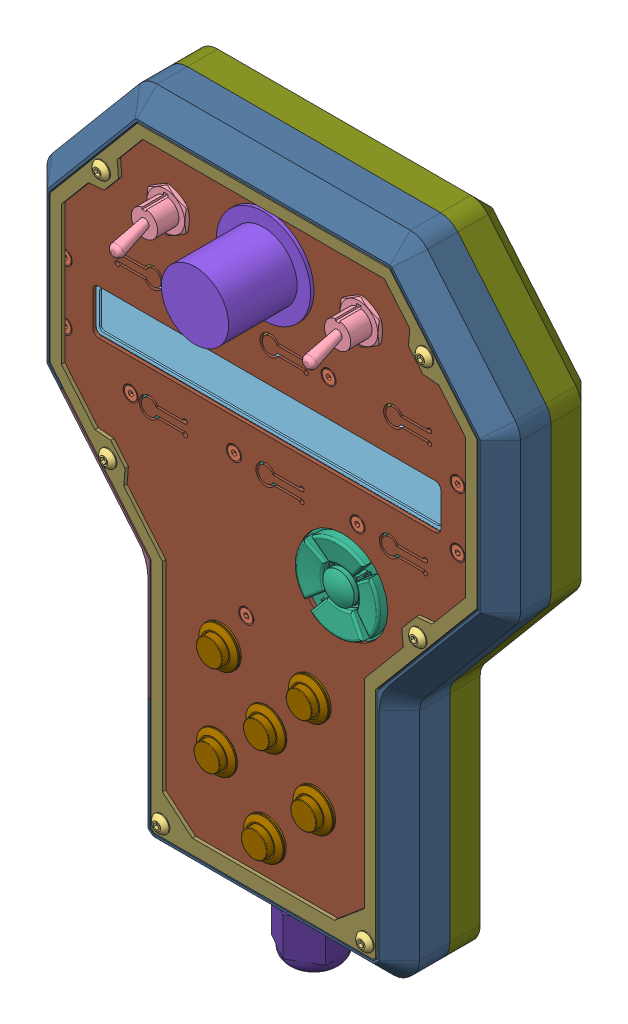
SolidWorks assembly Montagem, configuration Valor predeterminado. Lengths in mm.
Overall size (211 315 75.5).
59 component instances, 18 part files, 139 mates.
Components (placement in the parent):
- hex nut style 1 gradeab_din-3: hex nut style 1 gradeab_din [Hexagon Nut ISO 4032 - M4 - W - N] at (-95.2029 -0.5297 -15.05) x (-0.766044 -0.642788 0) z (0 0 1) size (7 8.08 3.2)
- hex nut style 1 gradeab_din-4: hex nut style 1 gradeab_din [Hexagon Nut ISO 4032 - M4 - W - N] at (42.9071 -0.5197 -15.05) x (0.766044 -0.642788 0) z (0 0 1) size (7 8.08 3.2)
- hex nut style 1 gradeab_din-5: hex nut style 1 gradeab_din [Hexagon Nut ISO 4032 - M4 - W - N] at (-69.6429 -49.9305 1.45) x (0.5 0.866025 0) z (0 0 1) size (7 8.08 3.2)
- hex nut style 1 gradeab_din-6: hex nut style 1 gradeab_din [Hexagon Nut ISO 4032 - M4 - W - N] at (33.6932 120.5695 1.45) x (0.766044 0.642788 0) z (0 0 1) size (7 8.08 3.2)
- hex nut style 1 gradeab_din-7: hex nut style 1 gradeab_din [Hexagon Nut ISO 4032 - M4 - W - N] at (17.3571 -99.7712 1.45) size (7 8.08 3.2)
- hex nut style 1 gradeab_din-8: hex nut style 1 gradeab_din [Hexagon Nut ISO 4032 - M4 - W - N] at (-85.979 120.5695 1.45) x (0.766044 -0.642788 0) z (0 0 1) size (7 8.08 3.2)
- hex nut style 1 gradeab_din-9: hex nut style 1 gradeab_din [Hexagon Nut ISO 4032 - M4 - W - N] at (-69.6429 -99.7712 1.45) size (7 8.08 3.2)
- hex nut style 1 gradeab_din-10: hex nut style 1 gradeab_din [Hexagon Nut ISO 4032 - M4 - W - N] at (45.8324 109.2141 -7.45) x (0.939693 -0.34202 0) z (0 0 -1) size (7 8.08 3.2)
- hex nut style 1 gradeab_din-11: hex nut style 1 gradeab_din [Hexagon Nut ISO 4032 - M4 - W - N] at (-71.6429 -129.7045 -7.45) x (0.5 0.866025 0) z (0 0 -1) size (7 8.08 3.2)
- hex nut style 1 gradeab_din-12: hex nut style 1 gradeab_din [Hexagon Nut ISO 4032 - M4 - W - N] at (19.3571 -129.7045 -7.45) x (1 0 0) z (0 0 -1) size (7 8.08 3.2)
- hex nut style 1 gradeab_din-13: hex nut style 1 gradeab_din [Hexagon Nut ISO 4032 - M4 - W - N] at (-98.1182 109.2141 -7.45) x (-0.939693 -0.34202 0) z (0 0 -1) size (7 8.08 3.2)
- socket countersunk head screw_din-8: socket countersunk head screw_din [DIN 7991 - M3 x 16 --- 12.8C] at (58.8311 39.2309 9.75) x (0 0 -1) z (1 0 0) size (16 5.7 5.7)
- socket countersunk head screw_din-9: socket countersunk head screw_din [DIN 7991 - M3 x 16 --- 12.8C] at (-86.7826 27.8805 9.75) x (0 0 -1) z (-0.923728 -0.383049 0) size (16 5.7 5.7)
- socket countersunk head screw_din-10: socket countersunk head screw_din [DIN 7991 - M3 x 16 --- 12.8C] at (-116.1689 65.7309 9.75) x (0 0 -1) z (-0.923728 -0.383049 0) size (16 5.7 5.7)
- socket countersunk head screw_din-11: socket countersunk head screw_din [DIN 7991 - M3 x 16 --- 12.8C] at (1.3536 78.245 9.75) x (0 0 -1) z (0.923728 0.383049 0) size (16 5.7 5.7)
- socket countersunk head screw_din-12: socket countersunk head screw_din [DIN 7991 - M3 x 16 --- 12.8C] at (-116.1689 39.2309 9.75) x (0 0 -1) z (-0.923728 -0.383049 0) size (16 5.7 5.7)
- socket countersunk head screw_din-13: socket countersunk head screw_din [DIN 7991 - M3 x 16 --- 12.8C] at (-50.6464 78.245 9.75) x (0 0 -1) z (0.923728 0.383049 0) size (16 5.7 5.7)
- socket countersunk head screw_din-14: socket countersunk head screw_din [DIN 7991 - M3 x 16 --- 12.8C] at (58.8311 65.7309 9.75) x (0 0 -1) z (0.923728 0.383049 0) size (16 5.7 5.7)
- socket countersunk head screw_din-15: socket countersunk head screw_din [DIN 7991 - M3 x 16 --- 12.8C] at (14.2174 27.8805 9.75) x (0 0 -1) z (1 0 0) size (16 5.7 5.7)
- socket countersunk head screw_din-16: socket countersunk head screw_din [DIN 7991 - M3 x 16 --- 12.8C] at (-40.7826 27.8805 9.75) x (0 0 -1) z (0.277326 0.960776 0) size (16 5.7 5.7)
- socket countersunk head screw_din-17: socket countersunk head screw_din [DIN 7991 - M3 x 16 --- 12.8C] at (-35.2826 -32.1195 9.75) x (0 0 -1) z (-0.305827 0.952087 0) size (16 5.7 5.7)
- hex nut style 1 gradeab_din-15: hex nut style 1 gradeab_din [Hexagon Nut ISO 4032 - M3 - W - N] at (-40.7826 27.8805 -1.3414) x (0.012479 -0.999922 0) z (0 0 -1) size (5.5 6.35 2.4)
- hex nut style 1 gradeab_din-16: hex nut style 1 gradeab_din [Hexagon Nut ISO 4032 - M3 - W - N] at (-50.6464 78.245 -1.3414) x (0.904381 -0.426726 0) z (0 0 -1) size (5.5 6.35 2.4)
- hex nut style 1 gradeab_din-17: hex nut style 1 gradeab_din [Hexagon Nut ISO 4032 - M3 - W - N] at (1.3536 78.245 -1.3414) x (-0.993944 0.109886 0) z (0 0 -1) size (5.5 6.35 2.4)
- hex nut style 1 gradeab_din-18: hex nut style 1 gradeab_din [Hexagon Nut ISO 4032 - M3 - W - N] at (14.2174 27.8805 -1.3414) x (-0.816279 -0.577658 0) z (0 0 -1) size (5.5 6.35 2.4)
- hex nut style 1 gradeab_din-19: hex nut style 1 gradeab_din [Hexagon Nut ISO 4032 - M3 - W - N] at (-86.7826 27.8805 -1.3414) x (-0.525463 -0.850817 0) z (0 0 -1) size (5.5 6.35 2.4)
- hex nut style 1 gradeab_din-20: hex nut style 1 gradeab_din [Hexagon Nut ISO 4032 - M3 - W - N] at (-116.1689 65.7309 -4.818) x (0.297598 -0.954691 0) z (0 0 -1) size (5.5 6.35 2.4)
- hex nut style 1 gradeab_din-21: hex nut style 1 gradeab_din [Hexagon Nut ISO 4032 - M3 - W - N] at (-116.1689 39.2309 -4.818) x (0.646896 0.762578 0) z (0 0 -1) size (5.5 6.35 2.4)
- hex nut style 1 gradeab_din-22: hex nut style 1 gradeab_din [Hexagon Nut ISO 4032 - M3 - W - N] at (58.8311 65.7309 -4.818) x (0.923728 0.383049 0) z (0 0 -1) size (5.5 6.35 2.4)
- hex nut style 1 gradeab_din-23: hex nut style 1 gradeab_din [Hexagon Nut ISO 4032 - M3 - W - N] at (58.8311 39.2309 -4.818) x (0.923728 0.383049 0) z (0 0 -1) size (5.5 6.35 2.4)
- hex nut style 1 gradeab_din-24: hex nut style 1 gradeab_din [Hexagon Nut ISO 4032 - M3 - W - N] at (-35.2826 -32.1195 -1.3414) x (0.05846 -0.99829 0) z (0 0 -1) size (5.5 6.35 2.4)
- socket button head screw_iso-9: socket button head screw_iso [ISO 7380 - M4 x 16 --- 16N] at (45.8295 109.2085 13.45) x (0 0 -1) z (1 0 0) size (18.2 7.6 7.6)
- socket button head screw_iso-10: socket button head screw_iso [ISO 7380 - M4 x 16 --- 16N] at (-98.1153 109.2085 13.45) x (0 0 -1) z (0.767389 -0.641182 0) size (18.2 7.6 7.6)
- socket button head screw_iso-11: socket button head screw_iso [ISO 7380 - M4 x 16 --- 16N] at (-71.6429 -129.7005 13.45) x (0 0 -1) z (1 0 0) size (18.2 7.6 7.6)
- socket button head screw_iso-12: socket button head screw_iso [ISO 7380 - M4 x 16 --- 16N] at (19.3571 -129.7005 13.45) x (0 0 -1) z (1 0 0) size (18.2 7.6 7.6)
- socket button head screw_iso-14: socket button head screw_iso [ISO 7380 - M4 x 16 --- 16N] at (-95.1957 -0.5218 13.45) x (0 0 -1) z (1 0 0) size (18.2 7.6 7.6)
- socket button head screw_iso-13: socket button head screw_iso [ISO 7380 - M4 x 16 --- 16N] at (42.9099 -0.5218 13.45) x (0 0 -1) z (1 0 0) size (18.2 7.6 7.6)
- BCV3 112 103 - Controle chave geral-1: BCV3 112 103 - Controle chave geral [Default] at (-69.1429 108.0695 0.25) size (17 29 51.5)
- BCV3 112 103 - Controle chave geral-2: BCV3 112 103 - Controle chave geral [Default] at (16.8571 108.0695 0.25) size (17 29 51.5)
- LCD Display 4002-1: LCD Display 4002 [Valor predeterminado] at (-28.6689 52.4809 -5.3644) size (182 33.5 13.65)
- PCB_IHM-1: PCB_IHM [Valor predeterminado] at (-53.4326 -36.6195 2.65) size (130.25 70.25 27.35)
- PCB_IHM_Teclas_Superiores-1: PCB_IHM_Teclas_Superiores [Valor predeterminado] at (-89.5964 71.826 2.65) size (130.25 12.75 19.2)
- Botão emergencia-1: Botão emergencia [Valor predeterminado] at (-26.1429 108.0695 -30.75) x (0.358985 -0.933343 0) z (-0.933343 -0.358985 0) size (42 72.5 42)
- AV16HA-1: AV16HA [Valor predeterminado] at (-26.1429 -112.9305 -4.3) x (0.991658 -0.128899 0) z (-0.128899 -0.991658 0) size (21.5 29.33 19.15)
- AV16HA-2: AV16HA [Valor predeterminado] at (-48.1429 -90.9305 -5.25) x (0.991658 -0.128901 0) z (-0.128901 -0.991658 0) size (21.5 29.33 19.15)
- AV16HA-3: AV16HA [Valor predeterminado] at (-4.1429 -90.9305 -4.3) x (0.991658 -0.128899 0) z (-0.128899 -0.991658 0) size (21.5 29.33 19.15)
- AV16HA-4: AV16HA [Valor predeterminado] at (-26.1429 -70.9305 -5.25) x (0.991658 -0.128899 0) z (-0.128899 -0.991658 0) size (21.5 29.33 19.15)
- AV16HA-5: AV16HA [Valor predeterminado] at (-46.1429 -48.9305 -4.3) x (0.999797 0.02015 0) z (0.02015 -0.999797 0) size (21.5 29.33 19.15)
- AV16HA-6: AV16HA [Valor predeterminado] at (-6.1429 -48.9305 -4.3) x (0.999457 -0.032936 0) z (-0.032936 -0.999457 0) size (21.5 29.33 19.15)
- TEC001 - Moldura -1: TEC001 - Moldura  [Valor predeterminado] at (-26.1429 -144.6278 -11.25) size (211 291 22.5)
- TEC002 - Placa Superior-1: TEC002 - Placa Superior [Valor predeterminado] at (-25.2999 1.2599 8.25) size (190 270 1.5)
- TEC003 - Moldura alumínio-1: TEC003 - Moldura alumínio [Valor predeterminado] at (-26.4426 -0.0902 9.75) size (190 270 1.5)
- TEC004 - Moldura Borracha-1: TEC004 - Moldura Borracha [Valor predeterminado] at (-26.6429 -144.6278 -11.25) size (64.1 110 22.5)
- TEC005 - Moldura Borracha Inferior-1: TEC005 - Moldura Borracha Inferior [Valor predeterminado] at (-26.6429 -144.6278 -11.25) size (64.1 110 22.5)
- TEC006 - Placa Inferior-1: TEC006 - Placa Inferior [Valor predeterminado] at (-25.2999 1.2599 -32.25) size (190 270 1.5)
- TEC007 - Moldura  Inferior-1: TEC007 - Moldura  Inferior [Valor predeterminado] at (-26.1429 -144.6278 -11.25) size (211 291 22.5)
- Prensa cabo-1: Prensa cabo [Valor predeterminado] at (-26.1429 -154.9305 -11.25) x (0.5 0 0.866025) z (0 -1 0) size (27.2 31.41 34)
- TEC008 - Pino-1: TEC008 - Pino [Valor predeterminado] at (-127.6429 32.3003 0.75) x (0.992574 0.121641 0) z (-0.121641 0.992574 0) size (4 25 4)
- TEC008 - Pino-2: TEC008 - Pino [Valor predeterminado] at (-80.1429 -114.1997 -24.25) x (0.610836 -0.791757 0) z (-0.791757 -0.610836 0) size (4 25 4)
Mates (geometry in assembly coordinates):
- Coincidente2: coincident aligned: plane of TEC001 - Moldura -1 through (-26.1429 -144.6278 11.25) normal (0 0 1); plane of Botão emergencia-1 through (-33.6816 127.6697 11.25) normal (0 0 1)
- Concêntrico1: concentric anti-aligned: circle of PCB_IHM-1; circle of TEC002 - Placa Superior-1
- Distância6: distance = 5.6 mm anti-aligned: plane of PCB_IHM-1 through (-53.5296 -36.7015 2.65) normal (0 0 1); plane of TEC002 - Placa Superior-1 through (-25.2999 1.2599 8.25) normal (0 0 -1)
- Coincidente16: coincident aligned: plane of PCB_IHM-1 through (-53.5296 -36.7015 2.65) normal (0 0 1); plane of PCB_IHM_Teclas_Superiores-1 through (-89.5964 71.699 2.65) normal (0 0 1)
- Paralelo1: parallel anti-aligned: plane of TEC001 - Moldura -1 through (-121.6429 88.9571 8.25) normal (1 0 0); plane of PCB_IHM-1 through (-91.5596 8.3805 1.0586) normal (-1 0 0)
- Distância7: distance = 1.5 mm aligned: plane of LCD Display 4002-1 through (-102.1429 60.5695 7.4626) normal (0 -1 0); plane of TEC002 - Placa Superior-1 through (-101.1429 62.0695 8.249) normal (0 -1 0)
- Coincidente22: coincident anti-aligned: plane of LCD Display 4002-1 through (-28.6689 52.4809 8.25) normal (0 0 1); plane of TEC002 - Placa Superior-1 through (-25.2999 1.2599 8.25) normal (0 0 -1)
- Distância8: distance = 1.5 mm aligned: plane of LCD Display 4002-1 through (-102.1429 43.8589 7.4626) normal (1 0 0); plane of TEC002 - Placa Superior-1 through (-103.6429 44.5695 8.249) normal (1 0 0)
- Coincidente24: coincident anti-aligned: plane of TEC001 - Moldura -1 through (-26.1429 -144.6278 8.25) normal (0 0 1); plane of TEC002 - Placa Superior-1 through (-25.2999 1.2599 8.25) normal (0 0 -1)
- Coincidente35: coincident anti-aligned: plane of TEC001 - Moldura -1 through (-49.8107 -84.1997 -11.25) normal (0 1 0); plane of TEC004 - Moldura Borracha-1 through (-50.3107 -84.1997 -11.25) normal (0 -1 0)
- Coincidente36: coincident anti-aligned: plane of TEC002 - Placa Superior-1 through (-25.2999 1.2599 8.25) normal (0 0 -1); plane of TEC004 - Moldura Borracha-1 through (-26.6429 -144.6278 8.25) normal (0 0 1)
- Concêntrico6: concentric aligned: cylinder of TEC002 - Placa Superior-1 through (-26.1429 -112.9305 8.249) axis (0 0 1) radius 8; cylinder of AV16HA-1 through (-26.1429 -112.9305 -4.3) axis (0 0 1) radius 7.95
- Tangente1: tangent: plane of TEC002 - Placa Superior-1 through (-25.2999 1.2599 9.75) normal (0 0 1); face of AV16HA-1
- Concêntrico7: concentric aligned: cylinder of TEC002 - Placa Superior-1 through (-46.1429 -48.9305 8.249) axis (0 0 1) radius 8; cylinder of AV16HA-5 through (-46.1429 -48.9305 -4.3) axis (0 0 1) radius 7.95
- Concêntrico8: concentric aligned: cylinder of TEC002 - Placa Superior-1 through (-6.1429 -48.9305 8.249) axis (0 0 1) radius 8; cylinder of AV16HA-6 through (-6.1429 -48.9305 -4.3) axis (0 0 1) radius 7.95
- Concêntrico9: concentric aligned: cylinder of TEC002 - Placa Superior-1 through (-26.1429 -70.9305 8.249) axis (0 0 1) radius 8; cylinder of AV16HA-4 through (-26.1429 -70.9305 -5.25) axis (0 0 1) radius 7.95
- Concêntrico10: concentric aligned: cylinder of TEC002 - Placa Superior-1 through (-4.1429 -90.9305 8.249) axis (0 0 1) radius 7.8948; cylinder of AV16HA-3 through (-4.1429 -90.9305 -4.3) axis (0 0 1) radius 7.95
- Concêntrico11: concentric aligned: cylinder of TEC002 - Placa Superior-1 through (-48.1429 -90.9305 8.249) axis (0 0 1) radius 7.3454; cylinder of AV16HA-2 through (-48.1429 -90.9305 -5.25) axis (0 0 1) radius 7.95
- Tangente2: tangent: plane of TEC002 - Placa Superior-1 through (-25.2999 1.2599 9.75) normal (0 0 1); face of AV16HA-5
- Tangente3: tangent: plane of TEC002 - Placa Superior-1 through (-25.2999 1.2599 9.75) normal (0 0 1); face of AV16HA-6
- Tangente4: tangent: plane of TEC002 - Placa Superior-1 through (-25.2999 1.2599 9.75) normal (0 0 1); face of AV16HA-4
- Tangente5: tangent: plane of TEC002 - Placa Superior-1 through (-25.2999 1.2599 9.75) normal (0 0 1); face of AV16HA-2
- Tangente6: tangent: plane of TEC002 - Placa Superior-1 through (-25.2999 1.2599 9.75) normal (0 0 1); face of AV16HA-3
- Concêntrico12: concentric anti-aligned: cylinder of Botão emergencia-1 through (-26.1429 108.0695 -53.2451) axis (0 0 -1) radius 15; cylinder of TEC002 - Placa Superior-1 through (-26.1429 108.0695 8.249) axis (0 0 1) radius 15
- Concêntrico13: concentric anti-aligned: cylinder of BCV3 112 103 - Controle chave geral-1 through (-69.1429 108.0695 21.25) axis (0 0 -1) radius 5.85; cylinder of TEC002 - Placa Superior-1 through (-69.1429 108.0695 8.249) axis (0 0 1) radius 6
- Concêntrico15: concentric anti-aligned: cylinder of BCV3 112 103 - Controle chave geral-2 through (16.8571 108.0695 21.25) axis (0 0 -1) radius 5.85; cylinder of TEC002 - Placa Superior-1 through (16.8571 108.0695 8.249) axis (0 0 1) radius 6
- Coincidente38: coincident anti-aligned: plane of BCV3 112 103 - Controle chave geral-1 through (-69.1429 117.8845 9.75) normal (0 0 -1); plane of TEC002 - Placa Superior-1 through (-25.2999 1.2599 9.75) normal (0 0 1)
- Coincidente39: coincident anti-aligned: plane of BCV3 112 103 - Controle chave geral-2 through (16.8571 117.8845 9.75) normal (0 0 -1); plane of TEC002 - Placa Superior-1 through (-25.2999 1.2599 9.75) normal (0 0 1)
- Coincidente40: coincident anti-aligned: plane of TEC001 - Moldura -1 through (-39.7429 -142.4305 -3.398) normal (0.5 0 -0.866025); plane of Prensa cabo-1 through (-39.7429 -142.4305 -3.398) normal (-0.5 0 0.866025)
- Coincidente41: coincident anti-aligned: plane of TEC001 - Moldura -1 through (-26.1429 -142.4305 4.4539) normal (-0.5 0 -0.866025); plane of Prensa cabo-1 through (-26.1429 -142.4305 4.4539) normal (0.5 0 0.866025)
- Coincidente42: coincident anti-aligned: plane of TEC001 - Moldura -1 through (-26.1429 -142.4305 -11.25) normal (0 1 0); plane of Prensa cabo-1 through (-26.1429 -142.4305 -11.25) normal (0 -1 0)
- Distância9: distance = 0.5 mm anti-aligned: plane of TEC002 - Placa Superior-1 through (-121.1429 88.7866 9.75) normal (-1 0 0); plane of TEC001 - Moldura -1 through (-121.6429 88.9571 8.25) normal (1 0 0)
- Distância10: distance = 0.5 mm anti-aligned: plane of TEC002 - Placa Superior-1 through (30.0211 135.0695 9.75) normal (0 1 0); plane of TEC001 - Moldura -1 through (30.2446 135.5695 8.25) normal (0 -1 0)
- Coincidente49: coincident anti-aligned: plane of TEC002 - Placa Superior-1 through (-25.2999 1.2599 9.75) normal (0 0 1); plane of TEC003 - Moldura alumínio-1 through (-26.4426 -0.0902 9.75) normal (0 0 -1)
- Coincidente50: coincident aligned: plane of TEC002 - Placa Superior-1 through (-121.1429 88.7866 9.75) normal (-1 0 0); plane of TEC003 - Moldura alumínio-1 through (-121.1429 88.7866 11.25) normal (-1 0 0)
- Coincidente51: coincident aligned: plane of TEC002 - Placa Superior-1 through (-74.8228 -134.9305 9.75) normal (0 -1 0); plane of TEC003 - Moldura alumínio-1 through (-74.8228 -134.9305 11.25) normal (0 -1 0)
- Coincidente52: coincident aligned: plane of TEC001 - Moldura -1 through (-86.6429 -144.6278 11.25) normal (-1 0 0); plane of TEC004 - Moldura Borracha-1 through (-86.6429 -144.6278 11.25) normal (-1 0 0)
- Coincidente53: coincident aligned: plane of TEC001 - Moldura -1 through (-26.1429 145.5695 11.25) normal (0 1 0); plane of TEC007 - Moldura  Inferior-1 through (-26.1429 145.5695 11.25) normal (0 1 0)
- Coincidente54: coincident aligned: plane of TEC001 - Moldura -1 through (-204.8631 5.3363 11.25) normal (-0.766044 0.642788 0); plane of TEC007 - Moldura  Inferior-1 through (-204.8631 5.3363 11.25) normal (-0.766044 0.642788 0)
- Coincidente55: coincident aligned: plane of TEC001 - Moldura -1 through (152.5774 5.3363 11.25) normal (0.766044 0.642788 0); plane of TEC007 - Moldura  Inferior-1 through (152.5774 5.3363 11.25) normal (0.766044 0.642788 0)
- Coincidente56: coincident anti-aligned: plane of TEC006 - Placa Inferior-1 through (-25.2999 1.2599 -30.75) normal (0 0 1); plane of TEC007 - Moldura  Inferior-1 through (-26.1429 -144.6278 -30.75) normal (0 0 -1)
- Distância11: distance = 0.5 mm anti-aligned: plane of TEC006 - Placa Inferior-1 through (30.0211 135.0695 -30.75) normal (0 1 0); plane of TEC007 - Moldura  Inferior-1 through (30.2446 135.5695 -30.75) normal (0 -1 0)
- Distância12: distance = 0.5 mm anti-aligned: plane of TEC006 - Placa Inferior-1 through (-121.1429 88.7866 -30.75) normal (-1 0 0); plane of TEC007 - Moldura  Inferior-1 through (-121.6429 88.9571 -30.75) normal (1 0 0)
- Coincidente57: coincident aligned: plane of TEC007 - Moldura  Inferior-1 through (-26.1429 -144.6278 -11.25) normal (0 0 1); plane of TEC005 - Moldura Borracha Inferior-1 through (-26.6429 -144.6278 -11.25) normal (0 0 1)
- Coincidente58: coincident anti-aligned: plane of TEC007 - Moldura  Inferior-1 through (-49.8107 -84.1997 -11.25) normal (0 1 0); plane of TEC005 - Moldura Borracha Inferior-1 through (-50.3107 -84.1997 -11.25) normal (0 -1 0)
- Coincidente59: coincident aligned: plane of TEC007 - Moldura  Inferior-1 through (-7.3536 -128.8618 11.25) normal (-0.766044 -0.642788 0); plane of TEC005 - Moldura Borracha Inferior-1 through (-7.5602 -128.6156 11.25) normal (-0.766044 -0.642788 0)
- Paralelo2: parallel anti-aligned: plane of TEC001 - Moldura -1 through (30.2446 135.5695 8.25) normal (0 -1 0); plane of BCV3 112 103 - Controle chave geral-1 through (-77.1429 122.5695 8.25) normal (0 1 0)
- Paralelo3: parallel anti-aligned: plane of TEC001 - Moldura -1 through (30.2446 135.5695 8.25) normal (0 -1 0); plane of BCV3 112 103 - Controle chave geral-2 through (8.8571 122.5695 8.25) normal (0 1 0)
- Concêntrico17: concentric aligned: cylinder of TEC001 - Moldura -1 through (33.6932 120.5695 -11.25) axis (0 0 1) radius 2.2; cylinder of hex nut style 1 gradeab_din-6 through (33.6932 120.5695 -1.75) axis (0 0 1) radius 1.65
- Concêntrico18: concentric aligned: cylinder of TEC001 - Moldura -1 through (-85.979 120.5695 -11.25) axis (0 0 1) radius 2.2; cylinder of hex nut style 1 gradeab_din-8 through (-85.979 120.5695 -1.75) axis (0 0 1) radius 1.65
- Paralelo4: parallel anti-aligned: plane of TEC001 - Moldura -1 through (-90.1865 121.3114 -1.75) normal (0.939693 0.34202 0); plane of hex nut style 1 gradeab_din-8 through (-89.9591 121.2713 -1.75) normal (-0.939693 -0.34202 0)
- Paralelo5: parallel anti-aligned: plane of TEC001 - Moldura -1 through (-87.4403 124.5843 -1.75) normal (0.766044 -0.642788 0); plane of hex nut style 1 gradeab_din-8 through (-87.3613 124.3672 -1.75) normal (-0.766044 0.642788 0)
- Coincidente67: coincident anti-aligned: plane of TEC001 - Moldura -1 through (-26.1429 -144.6278 -1.75) normal (0 0 1); plane of hex nut style 1 gradeab_din-8 through (-91.3414 125.069 -1.75) normal (0 0 -1)
- Paralelo6: parallel anti-aligned: plane of TEC001 - Moldura -1 through (30.947 123.8424 -1.75) normal (0.939693 -0.34202 0); plane of hex nut style 1 gradeab_din-6 through (31.0955 123.6655 -1.75) normal (-0.939693 0.34202 0)
- Coincidente69: coincident anti-aligned: plane of TEC001 - Moldura -1 through (-26.1429 -144.6278 -1.75) normal (0 0 1); plane of hex nut style 1 gradeab_din-6 through (28.3309 116.07 -1.75) normal (0 0 -1)
- Concêntrico21: concentric aligned: cylinder of TEC004 - Moldura Borracha-1 through (-69.6429 -49.9305 -11.25) axis (0 0 1) radius 2.2; cylinder of hex nut style 1 gradeab_din-5 through (-69.6429 -49.9305 -1.75) axis (0 0 1) radius 1.65
- Paralelo9: parallel aligned: plane of TEC004 - Moldura Borracha-1 through (-65.9429 -52.0667 -1.75) normal (-1 0 0); plane of hex nut style 1 gradeab_din-5 through (-73.1429 -47.9097 -1.75) normal (-1 0 0)
- Coincidente76: coincident anti-aligned: plane of TEC004 - Moldura Borracha-1 through (-26.6429 -144.6278 -1.75) normal (0 0 1); plane of hex nut style 1 gradeab_din-5 through (-73.1429 -55.9927 -1.75) normal (0 0 -1)
- Concêntrico22: concentric aligned: cylinder of TEC001 - Moldura -1 through (17.3571 -99.7712 -11.25) axis (0 0 1) radius 2.2; cylinder of hex nut style 1 gradeab_din-7 through (17.3571 -99.7712 -1.75) axis (0 0 1) radius 1.65
- Paralelo10: parallel aligned: plane of TEC001 - Moldura -1 through (21.0571 -101.9074 -1.75) normal (-1 0 0); plane of hex nut style 1 gradeab_din-7 through (13.8571 -97.7505 -1.75) normal (-1 0 0)
- Coincidente78: coincident anti-aligned: plane of TEC001 - Moldura -1 through (-26.1429 -144.6278 -1.75) normal (0 0 1); plane of hex nut style 1 gradeab_din-7 through (10.3571 -99.7712 -1.75) normal (0 0 -1)
- Concêntrico23: concentric aligned: cylinder of TEC001 - Moldura -1 through (-69.6429 -99.7712 -11.25) axis (0 0 1) radius 2.2; cylinder of hex nut style 1 gradeab_din-9 through (-69.6429 -99.7712 -1.75) axis (0 0 1) radius 1.65
- Paralelo11: parallel aligned: plane of TEC001 - Moldura -1 through (-65.9429 -101.9074 -1.75) normal (-1 0 0); plane of hex nut style 1 gradeab_din-9 through (-73.1429 -97.7505 -1.75) normal (-1 0 0)
- Coincidente80: coincident anti-aligned: plane of TEC001 - Moldura -1 through (-26.1429 -144.6278 -1.75) normal (0 0 1); plane of hex nut style 1 gradeab_din-9 through (-76.6429 -99.7712 -1.75) normal (0 0 -1)
- Concêntrico24: concentric anti-aligned: cylinder of TEC001 - Moldura -1 through (-71.6429 -129.7045 -11.25) axis (0 0 1) radius 2.2; cylinder of hex nut style 1 gradeab_din-11 through (-71.6429 -129.7045 -4.25) axis (0 0 -1) radius 1.65
- Paralelo12: parallel anti-aligned: plane of TEC001 - Moldura -1 through (-67.9429 -127.5683 3.75) normal (-0.5 -0.866025 0); plane of hex nut style 1 gradeab_din-11 through (-68.1429 -127.6838 -4.25) normal (0.5 0.866025 0)
- Concêntrico25: concentric anti-aligned: cylinder of TEC001 - Moldura -1 through (19.3571 -129.7045 -11.25) axis (0 0 1) radius 2.2; cylinder of hex nut style 1 gradeab_din-12 through (19.3571 -129.7045 -4.25) axis (0 0 -1) radius 1.65
- Paralelo13: parallel aligned: plane of TEC001 - Moldura -1 through (15.6571 -131.8407 3.75) normal (1 0 0); plane of hex nut style 1 gradeab_din-12 through (22.8571 -131.7252 -4.25) normal (1 0 0)
- Concêntrico27: concentric anti-aligned: cylinder of TEC001 - Moldura -1 through (45.8324 109.2141 -11.25) axis (0 0 1) radius 2.2; cylinder of hex nut style 1 gradeab_din-10 through (45.8324 109.2141 -4.25) axis (0 0 -1) radius 1.65
- Paralelo14: parallel aligned: plane of TEC001 - Moldura -1 through (43.0861 112.487 3.75) normal (0.173648 -0.984808 0); plane of hex nut style 1 gradeab_din-10 through (48.4302 106.1182 -4.25) normal (0.173648 -0.984808 0)
- Concêntrico28: concentric anti-aligned: cylinder of TEC001 - Moldura -1 through (-98.1182 109.2141 -11.25) axis (0 0 1) radius 2.2; cylinder of hex nut style 1 gradeab_din-13 through (-98.1182 109.2141 -4.25) axis (0 0 -1) radius 1.65
- Paralelo15: parallel aligned: plane of TEC001 - Moldura -1 through (-99.5794 113.2289 3.75) normal (-0.173648 -0.984808 0); plane of hex nut style 1 gradeab_din-13 through (-96.7359 105.4164 -4.25) normal (-0.173648 -0.984808 0)
- Coincidente89: coincident anti-aligned: plane of TEC001 - Moldura -1 through (-26.1429 -144.6278 -11.25) normal (0 0 -1); plane of TEC007 - Moldura  Inferior-1 through (-26.1429 -144.6278 -11.25) normal (0 0 1)
- Coincidente104: coincident anti-aligned: plane of PCB_IHM-1 through (-53.5296 -36.7015 1.0586) normal (0 0 -1); plane of hex nut style 1 gradeab_din-15 through (-43.9578 27.8409 1.0586) normal (0 0 1)
- Concêntrico53: concentric anti-aligned: cone of TEC002 - Placa Superior-1 through (14.2174 27.8805 9.75) axis (0 0 -1); cylinder of socket countersunk head screw_din-15 through (14.2174 27.8805 9.75) axis (0 0 1) radius 1.5
- Concêntrico54: concentric anti-aligned: cone of TEC002 - Placa Superior-1 through (58.8311 39.2309 9.75) axis (0 0 -1); cylinder of socket countersunk head screw_din-8 through (58.8311 39.2309 9.75) axis (0 0 1) radius 1.5
- Concêntrico55: concentric anti-aligned: cone of TEC002 - Placa Superior-1 through (58.8311 65.7309 9.75) axis (0 0 -1); cylinder of socket countersunk head screw_din-14 through (58.8311 65.7309 9.75) axis (0 0 1) radius 1.5
- Concêntrico56: concentric anti-aligned: cone of TEC002 - Placa Superior-1 through (1.3536 78.245 9.75) axis (0 0 -1); cylinder of socket countersunk head screw_din-11 through (1.3536 78.245 9.75) axis (0 0 1) radius 1.5
- Concêntrico57: concentric anti-aligned: cone of TEC002 - Placa Superior-1 through (-50.6464 78.245 9.75) axis (0 0 -1); cylinder of socket countersunk head screw_din-13 through (-50.6464 78.245 9.75) axis (0 0 1) radius 1.5
- Concêntrico58: concentric aligned: circle of TEC002 - Placa Superior-1; cylinder of socket countersunk head screw_din-10 through (-116.1689 65.7309 9.75) axis (0 0 1) radius 1.5
- Concêntrico59: concentric aligned: circle of TEC002 - Placa Superior-1; cylinder of socket countersunk head screw_din-12 through (-116.1689 39.2309 9.75) axis (0 0 1) radius 1.5
- Concêntrico60: concentric anti-aligned: cone of TEC002 - Placa Superior-1 through (-86.7826 27.8805 9.75) axis (0 0 -1); cylinder of socket countersunk head screw_din-9 through (-86.7826 27.8805 9.75) axis (0 0 1) radius 1.5
- Coincidente105: coincident aligned: plane of TEC002 - Placa Superior-1 through (-25.2999 1.2599 9.75) normal (0 0 1); plane of socket countersunk head screw_din-15 through (14.2174 27.8805 9.75) normal (0 0 1)
- Coincidente106: coincident aligned: plane of TEC002 - Placa Superior-1 through (-25.2999 1.2599 9.75) normal (0 0 1); plane of socket countersunk head screw_din-8 through (58.8311 39.2309 9.75) normal (0 0 1)
- Coincidente107: coincident: plane of TEC002 - Placa Superior-1 through (-25.2999 1.2599 9.75) normal (0 0 1); line of socket countersunk head screw_din-14 through (58.1215 64.8054 9.75) axis (-0.383049 0.923728 0)
- Coincidente108: coincident aligned: plane of TEC002 - Placa Superior-1 through (-25.2999 1.2599 9.75) normal (0 0 1); plane of socket countersunk head screw_din-11 through (1.3536 78.245 9.75) normal (0 0 1)
- Coincidente109: coincident aligned: plane of TEC002 - Placa Superior-1 through (-25.2999 1.2599 9.75) normal (0 0 1); plane of socket countersunk head screw_din-10 through (-116.1689 65.7309 9.75) normal (0 0 1)
- Coincidente110: coincident aligned: plane of TEC002 - Placa Superior-1 through (-25.2999 1.2599 9.75) normal (0 0 1); circle of socket countersunk head screw_din-13
- Coincidente111: coincident aligned: plane of TEC002 - Placa Superior-1 through (-25.2999 1.2599 9.75) normal (0 0 1); plane of socket countersunk head screw_din-9 through (-86.7826 27.8805 9.75) normal (0 0 1)
- Coincidente112: coincident aligned: plane of TEC002 - Placa Superior-1 through (-25.2999 1.2599 9.75) normal (0 0 1); plane of socket countersunk head screw_din-12 through (-116.1689 39.2309 9.75) normal (0 0 1)
- Concêntrico61: concentric anti-aligned: cone of TEC002 - Placa Superior-1 through (-40.7826 27.8805 9.75) axis (0 0 -1); cylinder of socket countersunk head screw_din-16 through (-40.7826 27.8805 9.75) axis (0 0 1) radius 1.5
- Coincidente113: coincident aligned: plane of TEC002 - Placa Superior-1 through (-25.2999 1.2599 9.75) normal (0 0 1); plane of socket countersunk head screw_din-16 through (-40.7826 27.8805 9.75) normal (0 0 1)
- Concêntrico62: concentric anti-aligned: cone of TEC002 - Placa Superior-1 through (-35.2826 -32.1195 9.75) axis (0 0 -1); cylinder of socket countersunk head screw_din-17 through (-35.2826 -32.1195 9.75) axis (0 0 1) radius 1.5
- Coincidente114: coincident aligned: plane of TEC002 - Placa Superior-1 through (-25.2999 1.2599 9.75) normal (0 0 1); plane of socket countersunk head screw_din-17 through (-35.2826 -32.1195 9.75) normal (0 0 1)
- Concêntrico63: concentric aligned: cone of socket countersunk head screw_din-13 through (-50.6464 78.245 -6.25) axis (0 0 -1); cylinder of hex nut style 1 gradeab_din-16 through (-50.6464 78.245 23.6961) axis (0 0 -1) radius 1.5
- Concêntrico64: concentric anti-aligned: cylinder of socket countersunk head screw_din-11 through (1.3536 78.245 9.75) axis (0 0 1) radius 1.5; cylinder of hex nut style 1 gradeab_din-17 through (1.3536 78.245 23.6961) axis (0 0 -1) radius 1.5
- Concêntrico65: concentric anti-aligned: cylinder of socket countersunk head screw_din-15 through (14.2174 27.8805 9.75) axis (0 0 1) radius 1.5; cylinder of hex nut style 1 gradeab_din-18 through (14.2174 27.8805 23.6961) axis (0 0 -1) radius 1.5
- Coincidente116: coincident anti-aligned: plane of PCB_IHM-1 through (-53.5296 -36.7015 1.0586) normal (0 0 -1); plane of hex nut style 1 gradeab_din-18 through (12.3831 30.4725 1.0586) normal (0 0 1)
- Concêntrico66: concentric anti-aligned: cylinder of socket countersunk head screw_din-9 through (-86.7826 27.8805 9.75) axis (0 0 1) radius 1.5; cylinder of hex nut style 1 gradeab_din-19 through (-86.7826 27.8805 23.6961) axis (0 0 -1) radius 1.5
- Coincidente117: coincident anti-aligned: plane of PCB_IHM-1 through (-53.5296 -36.7015 1.0586) normal (0 0 -1); plane of hex nut style 1 gradeab_din-19 through (-89.4843 29.5491 1.0586) normal (0 0 1)
- Concêntrico67: concentric anti-aligned: cylinder of socket countersunk head screw_din-10 through (-116.1689 65.7309 9.75) axis (0 0 1) radius 1.5; cylinder of hex nut style 1 gradeab_din-20 through (-116.1689 65.7309 20.2195) axis (0 0 -1) radius 1.5
- Coincidente118: coincident anti-aligned: plane of LCD Display 4002-1 through (-28.6689 52.4809 -2.418) normal (0 0 -1); plane of hex nut style 1 gradeab_din-20 through (-119.2005 64.7859 -2.418) normal (0 0 1)
- Concêntrico68: concentric anti-aligned: cylinder of socket countersunk head screw_din-12 through (-116.1689 39.2309 9.75) axis (0 0 1) radius 1.5; cylinder of hex nut style 1 gradeab_din-21 through (-116.1689 39.2309 20.2195) axis (0 0 -1) radius 1.5
- Coincidente119: coincident anti-aligned: plane of LCD Display 4002-1 through (-28.6689 52.4809 -2.418) normal (0 0 -1); plane of hex nut style 1 gradeab_din-21 through (-113.7474 37.1768 -2.418) normal (0 0 1)
- Concêntrico69: concentric anti-aligned: cylinder of socket countersunk head screw_din-14 through (58.8311 65.7309 9.75) axis (0 0 1) radius 1.5; cylinder of hex nut style 1 gradeab_din-22 through (58.8311 65.7309 20.2195) axis (0 0 -1) radius 1.5
- Coincidente120: coincident anti-aligned: plane of LCD Display 4002-1 through (-28.6689 52.4809 -2.418) normal (0 0 -1); plane of hex nut style 1 gradeab_din-22 through (60.0474 62.7977 -2.418) normal (0 0 1)
- Concêntrico70: concentric anti-aligned: cylinder of socket countersunk head screw_din-8 through (58.8311 39.2309 9.75) axis (0 0 1) radius 1.5; cylinder of hex nut style 1 gradeab_din-23 through (58.8311 39.2309 20.2195) axis (0 0 -1) radius 1.5
- Coincidente121: coincident anti-aligned: plane of LCD Display 4002-1 through (-28.6689 52.4809 -2.418) normal (0 0 -1); plane of hex nut style 1 gradeab_din-23 through (60.0474 36.2977 -2.418) normal (0 0 1)
- Concêntrico71: concentric anti-aligned: cylinder of socket countersunk head screw_din-17 through (-35.2826 -32.1195 9.75) axis (0 0 1) radius 1.5; cylinder of hex nut style 1 gradeab_din-24 through (-35.2826 -32.1195 1.0586) axis (0 0 -1) radius 1.25
- Coincidente123: coincident anti-aligned: plane of PCB_IHM-1 through (-53.5296 -36.7015 1.0586) normal (0 0 -1); plane of hex nut style 1 gradeab_din-24 through (-38.4526 -32.3052 1.0586) normal (0 0 1)
- Concêntrico72: concentric aligned: cylinder of TEC003 - Moldura alumínio-1 through (45.8295 109.2085 9.749) axis (0 0 1) radius 2.1; cylinder of socket button head screw_iso-9 through (45.8295 109.2085 13.45) axis (0 0 1) radius 3.8
- Coincidente124: coincident anti-aligned: plane of TEC003 - Moldura alumínio-1 through (-26.4426 -0.0902 11.25) normal (0 0 1); plane of socket button head screw_iso-9 through (45.8295 111.2085 11.25) normal (0 0 -1)
- Concêntrico73: concentric aligned: cylinder of TEC003 - Moldura alumínio-1 through (-98.1153 109.2085 9.749) axis (0 0 1) radius 2.1; cylinder of socket button head screw_iso-10 through (-98.1153 109.2085 13.45) axis (0 0 1) radius 3.8
- Coincidente125: coincident anti-aligned: plane of TEC003 - Moldura alumínio-1 through (-26.4426 -0.0902 11.25) normal (0 0 1); plane of socket button head screw_iso-10 through (-96.8329 110.7433 11.25) normal (0 0 -1)
- Concêntrico74: concentric aligned: cylinder of TEC003 - Moldura alumínio-1 through (-71.6429 -129.7005 9.749) axis (0 0 1) radius 2.1; cylinder of socket button head screw_iso-11 through (-71.6429 -129.7005 13.45) axis (0 0 1) radius 3.8
- Coincidente126: coincident anti-aligned: plane of TEC003 - Moldura alumínio-1 through (-26.4426 -0.0902 11.25) normal (0 0 1); plane of socket button head screw_iso-11 through (-71.6429 -127.7005 11.25) normal (0 0 -1)
- Concêntrico75: concentric aligned: cylinder of TEC003 - Moldura alumínio-1 through (19.3571 -129.7005 9.749) axis (0 0 1) radius 2.1; cylinder of socket button head screw_iso-12 through (19.3571 -129.7005 13.45) axis (0 0 1) radius 3.8
- Coincidente127: coincident anti-aligned: plane of TEC003 - Moldura alumínio-1 through (-26.4426 -0.0902 11.25) normal (0 0 1); plane of socket button head screw_iso-12 through (19.3571 -127.7005 11.25) normal (0 0 -1)
- Concêntrico76: concentric anti-aligned: cylinder of socket countersunk head screw_din-16 through (-40.7826 27.8805 9.75) axis (0 0 1) radius 1.5; cylinder of hex nut style 1 gradeab_din-15 through (-40.7826 27.8805 1.0586) axis (0 0 -1) radius 1.25
- Coincidente128: coincident anti-aligned: plane of hex nut style 1 gradeab_din-17 through (1.7025 81.4012 1.0586) normal (0 0 1); plane of PCB_IHM_Teclas_Superiores-1 through (-89.5964 71.699 1.0586) normal (0 0 -1)
- Coincidente131: coincident anti-aligned: plane of hex nut style 1 gradeab_din-16 through (-52.0015 75.3732 1.0586) normal (0 0 1); plane of PCB_IHM_Teclas_Superiores-1 through (-89.5964 71.699 1.0586) normal (0 0 -1)
- Concêntrico77: concentric aligned: cylinder of TEC007 - Moldura  Inferior-1 through (-127.6429 32.3003 -24.25) axis (0 0 1) radius 2.2; cylinder of TEC008 - Pino-1 through (-127.6429 32.3003 -24.25) axis (0 0 1) radius 2
- Coincidente138: coincident anti-aligned: plane of TEC007 - Moldura  Inferior-1 through (-127.6429 32.3003 -24.25) normal (0 0 1); plane of TEC008 - Pino-1 through (-127.6429 32.3003 -24.25) normal (0 0 -1)
- Concêntrico78: concentric anti-aligned: cylinder of TEC007 - Moldura  Inferior-1 through (-80.1429 -114.1997 -24.25) axis (0 0 1) radius 2.2; cylinder of TEC008 - Pino-2 through (-80.1429 -114.1997 0.75) axis (0 0 -1) radius 2
- Coincidente139: coincident anti-aligned: plane of TEC007 - Moldura  Inferior-1 through (-80.1429 -114.1997 -24.25) normal (0 0 1); plane of TEC008 - Pino-2 through (-80.1429 -114.1997 -24.25) normal (0 0 -1)
- Coincidente140: coincident anti-aligned: plane of TEC003 - Moldura alumínio-1 through (-26.4426 -0.0902 11.25) normal (0 0 1); plane of socket button head screw_iso-14 through (-95.1957 1.4782 11.25) normal (0 0 -1)
- Concêntrico80: concentric aligned: cylinder of TEC003 - Moldura alumínio-1 through (-95.1957 -0.5218 9.749) axis (0 0 1) radius 2.1; cylinder of socket button head screw_iso-14 through (-95.1957 -0.5218 13.45) axis (0 0 1) radius 2
- Coincidente141: coincident anti-aligned: plane of TEC003 - Moldura alumínio-1 through (-26.4426 -0.0902 11.25) normal (0 0 1); plane of socket button head screw_iso-13 through (42.9099 1.4782 11.25) normal (0 0 -1)
- Concêntrico82: concentric aligned: cylinder of TEC003 - Moldura alumínio-1 through (42.9099 -0.5218 9.749) axis (0 0 1) radius 2.1; cylinder of socket button head screw_iso-13 through (42.9099 -0.5218 13.45) axis (0 0 1) radius 2
- Concêntrico83: concentric anti-aligned: cylinder of hex nut style 1 gradeab_din-3 through (-95.2029 -0.5297 -18.25) axis (0 0 1) radius 1.65; cylinder of TEC005 - Moldura Borracha Inferior-1 through (-95.2029 -0.5297 -11.249) axis (0 0 -1) radius 2.1
- Paralelo16: parallel aligned: plane of hex nut style 1 gradeab_din-3 through (-96.5852 -4.3274 -18.25) normal (-0.766044 -0.642788 0); plane of TEC005 - Moldura Borracha Inferior-1 through (-90.9954 0.2122 -26.25) normal (-0.766044 -0.642788 0)
- Coincidente143: coincident: plane of hex nut style 1 gradeab_din-3 through (-89.8406 3.9698 -18.25) normal (0 0 -1); line of TEC005 - Moldura Borracha Inferior-1 through (-93.7417 3.485 -18.25) axis (0.642788 -0.766044 0)
- Concêntrico84: concentric aligned: cylinder of hex nut style 1 gradeab_din-4 through (42.9071 -0.5197 -18.25) axis (0 0 1) radius 1.65; cylinder of TEC007 - Moldura  Inferior-1 through (42.9071 -0.5197 -33.751) axis (0 0 1) radius 2.2
- Paralelo17: parallel aligned: plane of hex nut style 1 gradeab_din-4 through (46.8872 -1.2215 -18.25) normal (0.766044 -0.642788 0); plane of TEC007 - Moldura  Inferior-1 through (41.4459 3.495 -26.25) normal (0.766044 -0.642788 0)
- Coincidente145: coincident: plane of hex nut style 1 gradeab_din-4 through (37.5448 3.9798 -18.25) normal (0 0 -1); line of TEC007 - Moldura  Inferior-1 through (38.6996 0.2222 -18.25) axis (0.642788 0.766044 0)
- Coincidente146: coincident: plane of hex nut style 1 gradeab_din-10 through (39.2545 111.6083 -4.25) normal (0 0 1); line of TEC001 - Moldura -1 through (43.0861 112.487 -4.25) axis (-0.34202 -0.939693 0)
- Coincidente147: coincident: plane of hex nut style 1 gradeab_din-13 through (-91.5403 111.6083 -4.25) normal (0 0 1); line of TEC001 - Moldura -1 through (-99.5794 113.2289 -4.25) axis (-0.642788 -0.766044 0)
- Coincidente148: coincident: plane of hex nut style 1 gradeab_din-12 through (12.3571 -129.7045 -4.25) normal (0 0 1); moEndPointRef_w of TEC001 - Moldura -1
- Coincidente149: coincident: plane of hex nut style 1 gradeab_din-11 through (-75.1429 -135.7667 -4.25) normal (0 0 1); line of TEC001 - Moldura -1 through (-71.6429 -125.4321 -4.25) axis (-0.866025 -0.5 0)
